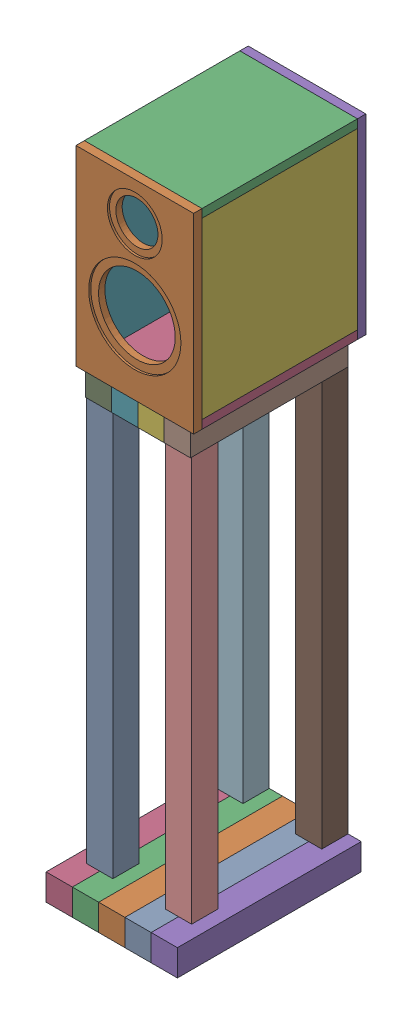
SolidWorks assembly stand, configuration Default. Lengths in mm.
Overall size (250 1234 370.2).
22 component instances, 7 part files, 15 mates.
Components (placement in the parent):
- Bottom-1: Bottom [Default] at (87.8591 -56.8141 -7.7634) size (250 50 350)
  - Lower-part-1: Lower-part [Default] at (-11.6531 84.0471 -50.9511) size (50 50 350)
  - Lower-part-2: Lower-part [Default] at (-61.6531 84.0471 -50.9511) size (50 50 350)
  - Lower-part-3: Lower-part [Default] at (-111.6531 84.0471 -50.9511) size (50 50 350)
  - Lower-part-4: Lower-part [Default] at (-161.6531 84.0471 -50.9511) size (50 50 350)
  - Lower-part-5: Lower-part [Default] at (38.3469 84.0471 -50.9511) size (50 50 350)
- Top-1: Top [Default] at (51.0333 847.233 -58.7145) size (200 50 300)
  - Upper-part-1: Upper-part [Default] at origin size (50 50 300)
  - Upper-part-2: Upper-part [Default] at (-50 0 0) size (50 50 300)
  - Upper-part-3: Upper-part [Default] at (50 0 0) size (50 50 300)
  - Upper-part-4: Upper-part [Default] at (-100 0 0) size (50 50 300)
- leg-1: leg [Default] at (101.0333 52.233 214.0667) size (50 770 50)
- leg-2: leg [Default] at (101.0333 52.233 -33.7145) size (50 770 50)
- leg-3: leg [Default] at (-48.9667 52.233 -33.7145) size (50 770 50)
- leg-4: leg [Default] at (-48.9667 52.233 214.0667) size (50 770 50)
- Assem1-1: Assem1 [Default] at (109.1206 1072.7425 177.6383) size (224 364 328)
  - face-1: face [Default] at (-81.251 -18.5095 55.4501) size (224 364 16)
  - top_bottom-1: top_bottom [Default] at (-81.251 147.4905 -92.5499) size (224 16 296)
  - top_bottom-2: top_bottom [Default] at (-81.251 -200.5095 -92.5499) size (224 16 296)
  - back-1: back [Default] at (-81.251 -18.5095 -256.5499) size (224 364 16)
  - left_right-1: left_right [Default] at (14.749 -18.5095 -92.5499) size (16 332 296)
  - left_right-2: left_right [Default] at (-193.251 -18.5095 -92.5499) size (16 332 296)
Mates (geometry in assembly coordinates):
- Coincident5: coincident aligned: plane of leg-1 through (101.0333 52.233 214.0667) normal (0 -1 0); plane of leg-3 through (-48.9667 52.233 -33.7145) normal (0 -1 0)
- Coincident6: coincident aligned: plane of leg-1 through (101.0333 52.233 214.0667) normal (0 -1 0); plane of leg-4 through (-48.9667 52.233 214.0667) normal (0 -1 0)
- Coincident7: coincident aligned: plane of leg-2 through (101.0333 52.233 -33.7145) normal (0 -1 0); plane of leg-4 through (-48.9667 52.233 214.0667) normal (0 -1 0)
- Coincident8: coincident anti-aligned: plane of Bottom-1/Lower-part-3 through (1.206 52.233 291.2855) normal (0 1 0); plane of leg-3 through (-48.9667 52.233 -33.7145) normal (0 -1 0)
- Coincident9: coincident anti-aligned: plane of Top-1/Upper-part-3 through (126.0333 822.233 241.2855) normal (0 -1 0); plane of leg-1 through (101.0333 822.233 214.0667) normal (0 1 0)
- Coincident10: coincident aligned: plane of Bottom-1/Lower-part-2 through (26.206 27.233 -58.7145) normal (0 0 -1); plane of Top-1/Upper-part-2 through (1.0333 847.233 -58.7145) normal (0 0 -1)
- Coincident11: coincident aligned: plane of leg-3 through (-73.9667 822.233 -8.7145) normal (-1 0 0); plane of leg-4 through (-73.9667 822.233 239.0667) normal (-1 0 0)
- Coincident12: coincident aligned: plane of leg-1 through (126.0333 822.233 239.0667) normal (1 0 0); plane of leg-2 through (126.0333 822.233 -8.7145) normal (1 0 0)
- Coincident13: coincident aligned: plane of leg-1 through (126.0333 822.233 239.0667) normal (0 0 1); plane of leg-4 through (-23.9667 822.233 239.0667) normal (0 0 1)
- Coincident14: coincident aligned: plane of leg-2 through (126.0333 822.233 -58.7145) normal (0 0 -1); plane of leg-3 through (-23.9667 822.233 -58.7145) normal (0 0 -1)
- Coincident15: coincident aligned: plane of Top-1/Upper-part-4 through (-73.9667 822.233 241.2855) normal (-1 0 0); plane of leg-3 through (-73.9667 822.233 -8.7145) normal (-1 0 0)
- Coincident16: coincident aligned: plane of Top-1/Upper-part-3 through (126.0333 822.233 241.2855) normal (1 0 0); plane of leg-2 through (126.0333 822.233 -8.7145) normal (1 0 0)
- Coincident17: coincident aligned: plane of Top-1/Upper-part-3 through (101.0333 847.233 -58.7145) normal (0 0 -1); plane of leg-2 through (126.0333 822.233 -58.7145) normal (0 0 -1)
- Coincident18: coincident aligned: plane of Bottom-1/Lower-part-1 through (76.206 27.233 -58.7145) normal (0 0 -1); plane of leg-2 through (126.0333 822.233 -58.7145) normal (0 0 -1)
- Coincident19: coincident anti-aligned: plane of Top-1/Upper-part-2 through (26.0333 872.233 241.2855) normal (0 1 0); plane of Assem1-1/top_bottom-2 through (27.8696 872.233 85.0884) normal (0 -1 0)
